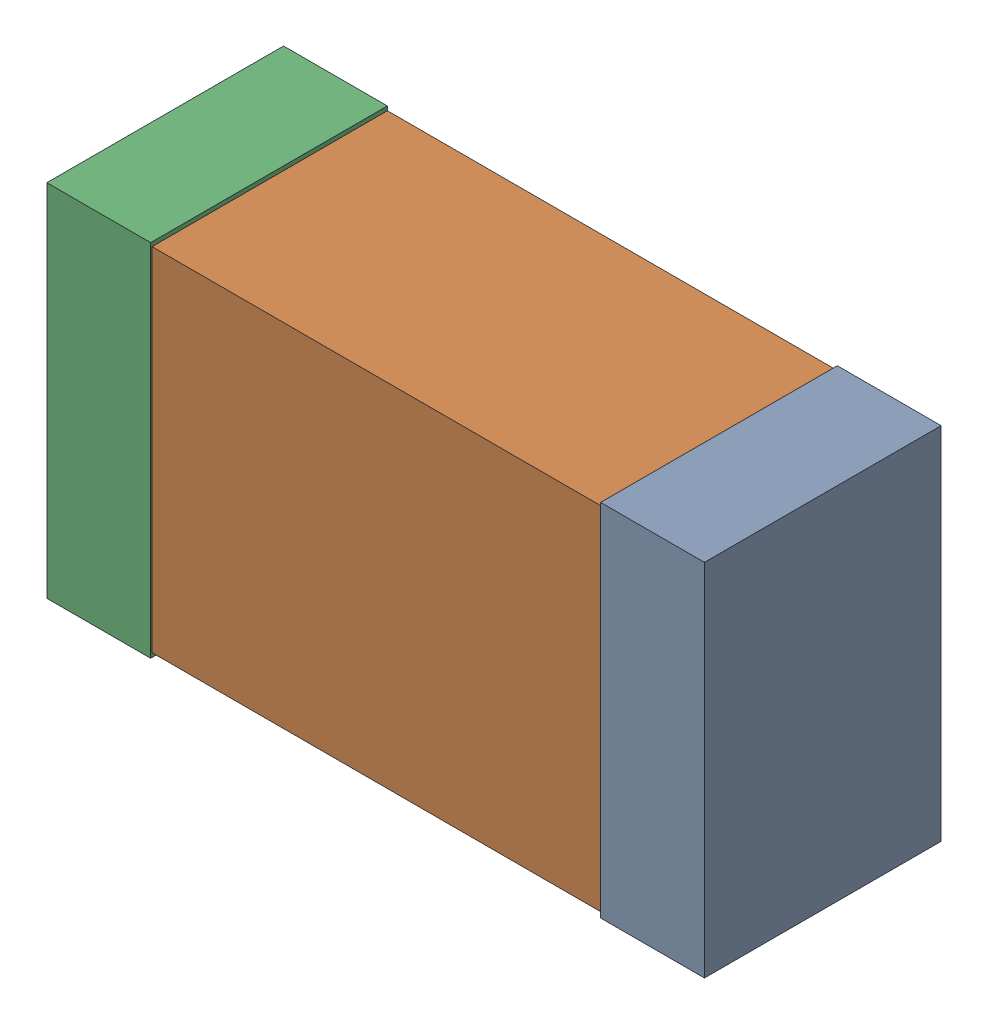
SolidWorks assembly RFBB12Kanaloa_v2.0.0_Power, configuration Default. Lengths in mm.
Overall size (2.38 1.3 0.85).
6 component instances, 2 part files, 0 mates.
Components (placement in the parent):
- 352877648-1: 352877648 [Default] at (49.26 128.016 0) size (0.38 1.3 0.85)
  - Extruded_14-1: Extruded_14 [Default] at origin size (0.38 1.3 0.85)
- 352877392-1: 352877392 [Default] at (48.26 128.016 0) size (2.2 1.27 0.85)
  - Extruded_15-1: Extruded_15 [Default] at origin size (2.2 1.27 0.85)
- 352877648-2: 352877648 [Default] at (47.26 128.016 0) size (0.38 1.3 0.85)
  - Extruded_14-1: Extruded_14 [Default] at origin size (0.38 1.3 0.85)
